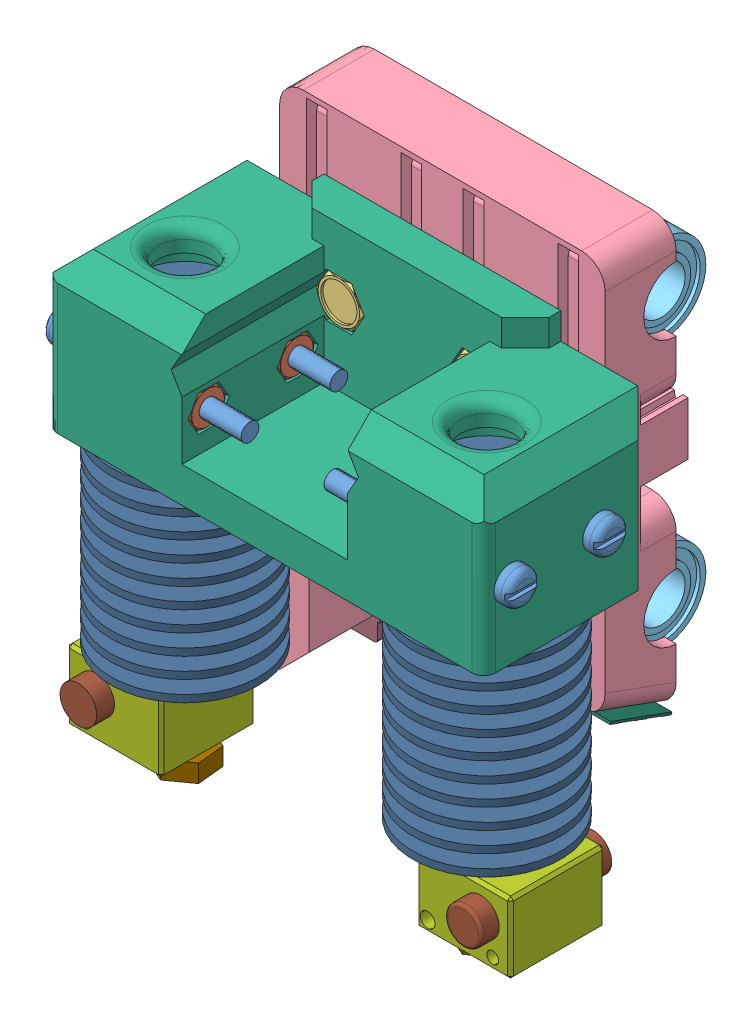
SolidWorks assembly extruder, configuration Défaut. Lengths in mm.
Overall size (79.79 92.4 60).
40 component instances, 15 part files, 73 mates.
Components (placement in the parent):
- pan slot head_am-1: pan slot head_am [B18.6.7M - M3 x 0.5 x 30 Slotted PHMS --30N] at (-39.4 4.5 25.5) size (32.4 5.6 5.6)
- pan slot head_am-2: pan slot head_am [B18.6.7M - M3 x 0.5 x 30 Slotted PHMS --30N] at (-39.4 4.5 10.5) size (32.4 5.6 5.6)
- pan slot head_am-3: pan slot head_am [B18.6.7M - M3 x 0.5 x 30 Slotted PHMS --30N] at (39.4 4.5 25.5) x (-1 0 0) z (0 0 1) size (32.4 5.6 5.6)
- pan slot head_am-4: pan slot head_am [B18.6.7M - M3 x 0.5 x 30 Slotted PHMS --30N] at (39.4 4.5 10.5) x (-1 0 0) z (0 0 1) size (32.4 5.6 5.6)
- hex nut style 1_am-1: hex nut style 1_am [B18.2.4.1M - Hex nut, Style 1,  M3 x 0.5 --D-N] at (-16.5 4.5 25.5) x (0 -1 0) z (-1 0 0) size (5.5 6.35 2.4)
- hex nut style 1_am-2: hex nut style 1_am [B18.2.4.1M - Hex nut, Style 1,  M3 x 0.5 --D-N] at (-16.5 4.5 10.5) x (0 -1 0) z (-1 0 0) size (5.5 6.35 2.4)
- hex nut style 1_am-3: hex nut style 1_am [B18.2.4.1M - Hex nut, Style 1,  M3 x 0.5 --D-N] at (16.5 4.5 25.5) x (0 -0.5 -0.866025) z (1 0 0) size (5.5 6.35 2.4)
- hex nut style 1_am-4: hex nut style 1_am [B18.2.4.1M - Hex nut, Style 1,  M3 x 0.5 --D-N] at (16.5 4.5 10.5) x (0 1 0) z (1 0 0) size (5.5 6.35 2.4)
- hex screw_am-3: hex screw_am [B18.6.7M - M4 x 0.7 x 20 Indented HHMS --20N] at (11.5 11.5 6) x (0 0 -1) z (0.866025 0.5 0) size (23 8.08 7)
- hex screw_am-4: hex screw_am [B18.6.7M - M4 x 0.7 x 20 Indented HHMS --20N] at (-11.5 11.5 6) x (0 0 -1) z (0.866025 -0.5 0) size (23 8.08 7)
- hex screw_am-5: hex screw_am [B18.6.7M - M4 x 0.7 x 20 Indented HHMS --20N] at (-11.5 -11.5 6) x (0 0 -1) z (0.866025 -0.5 0) size (23 8.08 7)
- hex screw_am-6: hex screw_am [B18.6.7M - M4 x 0.7 x 20 Indented HHMS --20N] at (11.5 -11.5 6) x (0 0 -1) z (0.866025 0.5 0) size (23 8.08 7)
- hex nut style 1_am-5: hex nut style 1_am [B18.2.4.1M - Hex nut, Style 1,  M4 x 0.7 --D-N] at (-11.5 11.5 -12) x (0.866025 -0.5 0) z (0 0 1) size (7 8.08 3.2)
- hex nut style 1_am-6: hex nut style 1_am [B18.2.4.1M - Hex nut, Style 1,  M4 x 0.7 --D-N] at (11.5 11.5 -12) x (0.866025 -0.5 0) z (0 0 1) size (7 8.08 3.2)
- hex nut style 1_am-7: hex nut style 1_am [B18.2.4.1M - Hex nut, Style 1,  M4 x 0.7 --D-N] at (11.5 -11.5 -12) x (0.866025 -0.5 0) z (0 0 1) size (7 8.08 3.2)
- hex nut style 1_am-8: hex nut style 1_am [B18.2.4.1M - Hex nut, Style 1,  M4 x 0.7 --D-N] at (-11.5 -11.5 -12) x (0.866025 -0.5 0) z (0 0 1) size (7 8.08 3.2)
- x_carriage-1: x_carriage [Défaut] at origin size (60 86.75 14)
- bearing_lm8uu-1: bearing_lm8uu [Défaut] at (25 22.5 -12) x (0 1 0) z (0 0 1) size (15 24 15)
- bearing_lm8uu-2: bearing_lm8uu [Défaut] at (-25 22.5 -12) x (0 1 0) z (0 0 -1) size (15 24 15)
- bearing_lm8uu-3: bearing_lm8uu [Défaut] at (25 -22.5 -12) x (0 -1 0) z (0 0 -1) size (15 24 15)
- bearing_lm8uu-4: bearing_lm8uu [Défaut] at (-25 -22.5 -12) x (0 -1 0) z (0 0 1) size (15 24 15)
- extruder_holder-1: extruder_holder [Défaut] at (-20 3 6) x (-1 0 0) z (0 0 -1) size (74 40 30)
- E3D-1: E3D [Default] at (-29.5 -53.4 18) x (-1 0 0) z (0 0 -1) size (28.79 69.7 37.75)
  - E3D Heat Block-1: E3D Heat Block [Default] at origin size (16 12 16)
  - E3D Heatbreak-1: E3D Heatbreak [Default] at (-4 19.55 0) x (-0.93266 0 -0.360757) z (-0.360757 0 0.93266) size (6 25.1 6)
  - E3D Nozzle-1: E3D Nozzle [Default] at (-4 -3.5 0) x (-0.097107 0 -0.995274) z (0.995274 0 -0.097107) size (9.24 12.5 8)
  - E3D Heatsink-1: E3D Heatsink [1.75 Bowden] at (-4 39.15 0) x (0.986263 0 -0.165183) z (0.165183 0 0.986263) size (25 50.1 25)
  - cartridge heater-1: cartridge heater [Default] at (3 7 0) x (0 0 1) z (-0.150948 -0.988542 0) size (32 6.2 6.2)
  - thermistor-1: thermistor [Default] at (-6 2 6.5) x (-0.997586 0.069447 0) z (-0.069447 -0.997586 0) size (2 13.25 2)
- E3D-2: E3D [Default] at (29.5 -53.4 18) size (28.79 69.7 37.75)
  - E3D Heat Block-1: E3D Heat Block [Default] at origin size (16 12 16)
  - E3D Heatbreak-1: E3D Heatbreak [Default] at (-4 19.55 0) x (-0.93266 0 -0.360757) z (-0.360757 0 0.93266) size (6 25.1 6)
  - E3D Nozzle-1: E3D Nozzle [Default] at (-4 -3.5 0) x (-0.097107 0 -0.995274) z (0.995274 0 -0.097107) size (9.24 12.5 8)
  - E3D Heatsink-1: E3D Heatsink [1.75 Bowden] at (-4 39.15 0) x (0.986263 0 -0.165183) z (0.165183 0 0.986263) size (25 50.1 25)
  - cartridge heater-1: cartridge heater [Default] at (3 7 0) x (0 0 1) z (-0.150948 -0.988542 0) size (32 6.2 6.2)
  - thermistor-1: thermistor [Default] at (-6 2 6.5) x (-0.997586 0.069447 0) z (-0.069447 -0.997586 0) size (2 13.25 2)
- kw4A(S) microswitch-1: kw4A(S) microswitch [Default] at (-22.975 -43.25 -18.5) x (0 0 1) z (0 -1 0) size (6.5 20.24 21.62)
- socket head cap screw_am-1: socket head cap screw_am [B18.3.1M - 2.5 x 0.45 x 10 Hex SHCS -- 10NHX] at (-25.5 -38.4 -21) x (0 0 1) z (-0.866025 -0.5 0) size (12.5 4.5 4.5)
- socket head cap screw_am-2: socket head cap screw_am [B18.3.1M - 2.5 x 0.45 x 10 Hex SHCS -- 10NHX] at (-25.5 -48.1 -21) x (0 0 1) z (-0.866025 -0.5 0) size (12.5 4.5 4.5)
- flexstripe24v-1: flexstripe24v [Default] at (2.5 -35.7231 -6.108) x (1 0 0) z (0 -0.34202 -0.939693) size (50 1.9 11)
Mates (geometry in assembly coordinates):
- Coaxiale1: concentric aligned: cylinder of x_carriage-1 through (1 22.5 -12) axis (1 0 0) radius 7.5; cylinder of bearing_lm8uu-1 through (13 22.5 -12) axis (1 0 0) radius 7.5
- Coïncidente1: coincident anti-aligned: plane of x_carriage-1 through (1 22.5 -12) normal (1 0 0); plane of bearing_lm8uu-1 through (1 22.5 -12) normal (-1 0 0)
- Parallèle1: parallel aligned: plane of bearing_lm8uu-1 through (25 22.5 -12) normal (0 0 1); plane of assembly through (0 0 0) normal (0 0 1)
- Coïncidente3: coincident anti-aligned: plane of x_carriage-1 through (0 0 0) normal (0 0 1); plane of extruder_holder-1 through (-20 3 0) normal (0 0 -1)
- Parallèle2: parallel anti-aligned: plane of extruder_holder-1 through (-20 3 6) normal (-1 0 0); plane of assembly through (0 0 0) normal (1 0 0)
- Coaxiale2: concentric anti-aligned: cylinder of x_carriage-1 through (-11.5 11.5 -14) axis (0 0 1) radius 2.5; cylinder of extruder_holder-1 through (-11.5 11.5 30) axis (0 0 -1) radius 2.5
- Coaxiale3: concentric aligned: cylinder of E3D-1/E3D Heatsink-1 through (-25.5 -39.3 18) axis (0 -1 0) radius 6; cylinder of extruder_holder-1 through (-25.5 18.5 18) axis (0 -1 0) radius 4.5
- Parallèle3: parallel aligned: plane of E3D-1/E3D Heat Block-1 through (-37.5 -41.4 10) normal (-1 0 0); plane of extruder_holder-1 through (-37 -1.5 30) normal (-1 0 0)
- Coaxiale4: concentric aligned: cylinder of extruder_holder-1 through (25.5 18.5 18) axis (0 -1 0) radius 4.5; cylinder of E3D-2/E3D Heatsink-1 through (25.5 -39.3 18) axis (0 -1 0) radius 8
- Parallèle4: parallel aligned: plane of extruder_holder-1 through (37 -1.5 30) normal (1 0 0); plane of E3D-2/E3D Heat Block-1 through (37.5 -41.4 26) normal (1 0 0)
- Coaxiale5: concentric aligned: cylinder of extruder_holder-1 through (-9.0503 4.5 25.5) axis (-1 0 0) radius 1.75; cylinder of pan slot head_am-1 through (-64.8 4.5 25.5) axis (-1 0 0) radius 2.8
- Coïncidente7: coincident anti-aligned: plane of extruder_holder-1 through (-37 -1.5 30) normal (-1 0 0); plane of pan slot head_am-1 through (-37 6 25.5) normal (1 0 0)
- Coaxiale6: concentric aligned: cylinder of extruder_holder-1 through (-9.0503 4.5 10.5) axis (-1 0 0) radius 1.75; cylinder of pan slot head_am-2 through (-64.8 4.5 10.5) axis (-1 0 0) radius 2.8
- Coïncidente8: coincident anti-aligned: plane of extruder_holder-1 through (-37 -1.5 30) normal (-1 0 0); plane of pan slot head_am-2 through (-37 6 10.5) normal (1 0 0)
- Coaxiale7: concentric aligned: cylinder of extruder_holder-1 through (9.0503 4.5 25.5) axis (1 0 0) radius 1.75; cylinder of pan slot head_am-3 through (64.8 4.5 25.5) axis (1 0 0) radius 2.8
- Coïncidente9: coincident anti-aligned: plane of extruder_holder-1 through (37 -1.5 30) normal (1 0 0); plane of pan slot head_am-3 through (37 3 25.5) normal (-1 0 0)
- Coaxiale8: concentric aligned: cylinder of extruder_holder-1 through (9.0503 4.5 10.5) axis (1 0 0) radius 1.75; cylinder of pan slot head_am-4 through (64.8 4.5 10.5) axis (1 0 0) radius 2.8
- Coïncidente10: coincident anti-aligned: plane of extruder_holder-1 through (37 -1.5 30) normal (1 0 0); plane of pan slot head_am-4 through (37 3 10.5) normal (-1 0 0)
- Coaxiale9: concentric aligned: cylinder of pan slot head_am-1 through (-64.8 4.5 25.5) axis (-1 0 0) radius 1.5; cylinder of hex nut style 1_am-1 through (8.5375 4.5 25.5) axis (-1 0 0) radius 1.5
- Coaxiale10: concentric aligned: cylinder of pan slot head_am-2 through (-64.8 4.5 10.5) axis (-1 0 0) radius 1.5; cylinder of hex nut style 1_am-2 through (8.5375 4.5 10.5) axis (-1 0 0) radius 1.5
- Coaxiale11: concentric aligned: cylinder of pan slot head_am-3 through (64.8 4.5 25.5) axis (1 0 0) radius 1.5; cylinder of hex nut style 1_am-3 through (-8.5375 4.5 25.5) axis (1 0 0) radius 1.5
- Coaxiale12: concentric aligned: cylinder of pan slot head_am-4 through (64.8 4.5 10.5) axis (1 0 0) radius 1.5; cylinder of hex nut style 1_am-4 through (-8.5375 4.5 10.5) axis (1 0 0) radius 1.5
- Coïncidente11: coincident anti-aligned: plane of extruder_holder-1 through (-16.5 3 6) normal (1 0 0); plane of hex nut style 1_am-2 through (-16.5 4.5 13.6754) normal (-1 0 0)
- Coïncidente12: coincident anti-aligned: plane of extruder_holder-1 through (-16.5 3 6) normal (1 0 0); plane of hex nut style 1_am-1 through (-16.5 4.5 28.6754) normal (-1 0 0)
- Coïncidente13: coincident anti-aligned: plane of extruder_holder-1 through (16.5 3 6) normal (-1 0 0); plane of hex nut style 1_am-3 through (16.5 7.25 23.9123) normal (1 0 0)
- Coïncidente14: coincident anti-aligned: plane of extruder_holder-1 through (16.5 3 6) normal (-1 0 0); plane of hex nut style 1_am-4 through (16.5 4.5 13.6754) normal (1 0 0)
- Parallèle5: parallel aligned: plane of extruder_holder-1 through (-16.5 4.5 22.0359) normal (0 -0.5 0.866025); plane of hex nut style 1_am-1 through (-14.1 1.75 27.0877) normal (0 -0.5 0.866025)
- Parallèle6: parallel aligned: plane of extruder_holder-1 through (-16.5 4.5 7.0359) normal (0 -0.5 0.866025); plane of hex nut style 1_am-2 through (-14.1 1.75 12.0877) normal (0 -0.5 0.866025)
- Coaxiale13: concentric anti-aligned: cylinder of extruder_holder-1 through (11.5 11.5 30) axis (0 0 -1) radius 2.5; cylinder of hex screw_am-3 through (11.5 11.5 31.4) axis (0 0 1) radius 2
- Coïncidente15: coincident anti-aligned: plane of extruder_holder-1 through (-20 3 3) normal (0 0 1); plane of hex screw_am-3 through (10.5 13.2321 3) normal (0 0 -1)
- Coaxiale14: concentric anti-aligned: cylinder of extruder_holder-1 through (-11.5 11.5 30) axis (0 0 -1) radius 2.5; cylinder of hex screw_am-4 through (-11.5 11.5 31.4) axis (0 0 1) radius 2
- Coïncidente16: coincident anti-aligned: plane of extruder_holder-1 through (-20 3 3) normal (0 0 1); plane of hex screw_am-4 through (-10.5 13.2321 3) normal (0 0 -1)
- Coaxiale15: concentric anti-aligned: cylinder of extruder_holder-1 through (-11.5 -11.5 30) axis (0 0 -1) radius 2.5; cylinder of hex screw_am-5 through (-11.5 -11.5 31.4) axis (0 0 1) radius 2
- Coïncidente17: coincident anti-aligned: plane of extruder_holder-1 through (-20 3 3) normal (0 0 1); plane of hex screw_am-5 through (-10.5 -9.7679 3) normal (0 0 -1)
- Coaxiale16: concentric anti-aligned: cylinder of extruder_holder-1 through (11.5 -11.5 30) axis (0 0 -1) radius 2.5; cylinder of hex screw_am-6 through (11.5 -11.5 31.4) axis (0 0 1) radius 2
- Coïncidente18: coincident anti-aligned: plane of extruder_holder-1 through (-20 3 3) normal (0 0 1); plane of hex screw_am-6 through (10.5 -9.7679 3) normal (0 0 -1)
- Parallèle7: parallel aligned: plane of extruder_holder-1 through (-13.6651 15.25 30) normal (0.866025 -0.5 0); plane of hex screw_am-4 through (-9.4793 8 3) normal (0.866025 -0.5 0)
- Parallèle8: parallel aligned: plane of extruder_holder-1 through (-13.6651 -7.75 30) normal (0.866025 -0.5 0); plane of hex screw_am-5 through (-9.4793 -15 3) normal (0.866025 -0.5 0)
- Parallèle9: parallel aligned: plane of extruder_holder-1 through (15.8301 11.5 30) normal (-0.866025 -0.5 0); plane of hex screw_am-3 through (7.4585 11.5 3) normal (-0.866025 -0.5 0)
- Parallèle10: parallel aligned: plane of extruder_holder-1 through (15.8301 -11.5 30) normal (-0.866025 -0.5 0); plane of hex screw_am-6 through (7.4585 -11.5 3) normal (-0.866025 -0.5 0)
- Coaxiale17: concentric aligned: cylinder of hex screw_am-4 through (-11.5 11.5 31.4) axis (0 0 1) radius 2; cylinder of hex nut style 1_am-5 through (-11.5 11.5 -37.0375) axis (0 0 1) radius 2
- Coaxiale18: concentric aligned: cylinder of hex screw_am-3 through (11.5 11.5 31.4) axis (0 0 1) radius 2; cylinder of hex nut style 1_am-6 through (11.5 11.5 -37.0375) axis (0 0 1) radius 2
- Coaxiale19: concentric aligned: cylinder of hex screw_am-6 through (11.5 -11.5 31.4) axis (0 0 1) radius 2; cylinder of hex nut style 1_am-7 through (11.5 -11.5 -37.0375) axis (0 0 1) radius 2
- Coaxiale20: concentric aligned: cylinder of hex screw_am-5 through (-11.5 -11.5 31.4) axis (0 0 1) radius 2; cylinder of hex nut style 1_am-8 through (-11.5 -11.5 -37.0375) axis (0 0 1) radius 2
- Coïncidente20: coincident anti-aligned: plane of x_carriage-1 through (0 0 -12) normal (0 0 -1); plane of hex nut style 1_am-6 through (5.4378 15 -12) normal (0 0 1)
- Coïncidente21: coincident anti-aligned: plane of x_carriage-1 through (0 0 -12) normal (0 0 -1); plane of hex nut style 1_am-5 through (-17.5622 15 -12) normal (0 0 1)
- Coïncidente22: coincident anti-aligned: plane of x_carriage-1 through (0 0 -12) normal (0 0 -1); plane of hex nut style 1_am-7 through (5.4378 -8 -12) normal (0 0 1)
- Coïncidente23: coincident anti-aligned: plane of x_carriage-1 through (0 0 -12) normal (0 0 -1); plane of hex nut style 1_am-8 through (-17.5622 -8 -12) normal (0 0 1)
- Parallèle12: parallel aligned: plane of x_carriage-1 through (27.5 -7.5 -12) normal (0 1 0); plane of hex nut style 1_am-7 through (13.5207 -8 -15.2) normal (0 1 0)
- Parallèle13: parallel aligned: plane of x_carriage-1 through (27.5 -7.5 -12) normal (0 1 0); plane of hex nut style 1_am-8 through (-9.4793 -8 -15.2) normal (0 1 0)
- Parallèle14: parallel aligned: plane of x_carriage-1 through (27.5 7.5 -12) normal (0 -1 0); plane of hex nut style 1_am-6 through (9.4793 8 -15.2) normal (0 -1 0)
- Parallèle15: parallel aligned: plane of x_carriage-1 through (27.5 7.5 -12) normal (0 -1 0); plane of hex nut style 1_am-5 through (-13.5207 8 -15.2) normal (0 -1 0)
- Parallèle16: parallel aligned: line of pan slot head_am-1 through (-38.7 4 22.856) axis (0 0 1); line of pan slot head_am-2 through (-38.7 4 7.856) axis (0 0 1)
- Parallèle17: parallel anti-aligned: line of extruder_holder-1 through (-37 -7.5 28) axis (0 0 -1); line of pan slot head_am-2 through (-38.7 4 7.856) axis (0 0 1)
- Parallèle18: parallel anti-aligned: plane of extruder_holder-1 through (16.5 7.5 23.7679) normal (0 -1 0); plane of hex nut style 1_am-3 through (14.1 7.25 23.9123) normal (0 1 0)
- Parallèle19: parallel aligned: plane of extruder_holder-1 through (16.5 4.5 7.0359) normal (0 -0.5 0.866025); plane of hex nut style 1_am-4 through (14.1 4.5 13.6754) normal (0 -0.5 0.866025)
- Parallèle20: parallel aligned: line of pan slot head_am-3 through (38.7 5 22.856) axis (0 0 1); line of pan slot head_am-4 through (38.7 5 7.856) axis (0 0 1)
- Parallèle21: parallel anti-aligned: line of extruder_holder-1 through (37 -7.5 28) axis (0 0 -1); line of pan slot head_am-3 through (38.7 5 22.856) axis (0 0 1)
- Coïncidente25: coincident anti-aligned: plane of x_carriage-1 through (0 0 -12) normal (0 0 -1); plane of kw4A(S) microswitch-1 through (-31.995 -34 -12) normal (0 0 1)
- Parallèle23: parallel aligned: plane of x_carriage-1 through (-27.5 33.5 -6) normal (0 1 0); plane of kw4A(S) microswitch-1 through (-31.995 -33.5 -12) normal (0 1 0)
- Coaxiale21: concentric aligned: cylinder of kw4A(S) microswitch-1 through (-25.5 -38.4 -12) axis (0 0 -1) radius 1.275; cylinder of socket head cap screw_am-1 through (-25.5 -38.4 -52.75) axis (0 0 -1) radius 2.25
- Coïncidente28: coincident anti-aligned: plane of kw4A(S) microswitch-1 through (-31.995 -34 -18.5) normal (0 0 -1); plane of socket head cap screw_am-1 through (-26.625 -36.4514 -18.5) normal (0 0 1)
- Coaxiale22: concentric aligned: cylinder of kw4A(S) microswitch-1 through (-25.5 -48.1 -12) axis (0 0 -1) radius 1.275; cylinder of socket head cap screw_am-2 through (-25.5 -48.1 -52.75) axis (0 0 -1) radius 2.25
- Coïncidente29: coincident anti-aligned: plane of kw4A(S) microswitch-1 through (-31.995 -34 -18.5) normal (0 0 -1); plane of socket head cap screw_am-2 through (-26.625 -46.1514 -18.5) normal (0 0 1)
- Parallèle24: parallel aligned: plane of socket head cap screw_am-1 through (-26.0903 -39.4225 -19.9) normal (0 1 0); plane of socket head cap screw_am-2 through (-26.0903 -49.1225 -19.9) normal (0 1 0)
- Parallèle25: parallel aligned: plane of kw4A(S) microswitch-1 through (-31.995 -33.5 -12) normal (0 1 0); plane of socket head cap screw_am-1 through (-26.0903 -39.4225 -19.9) normal (0 1 0)
- Coaxiale23: concentric anti-aligned: cylinder of x_carriage-1 through (-25.5 -38.4 -8) axis (0 0 -1) radius 1; circle of kw4A(S) microswitch-1
- Coïncidente31: coincident anti-aligned: plane of x_carriage-1 through (27.5 -37.8676 -12) normal (0 -0.939693 0.34202); plane of flexstripe24v-1 through (2.5 -35.7231 -6.108) normal (0 0.939693 -0.34202)
- Parallèle26: parallel anti-aligned: line of x_carriage-1 through (-22.5 -33.5 0) axis (1 0 0); line of flexstripe24v-1 through (27.5 -33.842 -0.9397) axis (-1 0 0)
- Coïncidente32: coincident anti-aligned: plane of x_carriage-1 through (-22.5 -53.25 0) normal (1 0 0); plane of flexstripe24v-1 through (-22.5 -37.9801 -11.1395) normal (-1 0 0)
- Distance1: distance = 1 mm: line of flexstripe24v-1 through (27.5 -33.842 -0.9397) axis (-1 0 0); line of x_carriage-1 through (-22.5 -33.5 0) axis (1 0 0)
- Coïncidente33: coincident anti-aligned: plane of extruder_holder-1 through (-20 -7.5 6) normal (0 -1 0); plane of E3D-1/E3D Heatsink-1 through (-37.8283 -7.5 20.0648) normal (0 1 0)
- Coïncidente34: coincident anti-aligned: plane of extruder_holder-1 through (-20 -7.5 6) normal (0 -1 0); plane of E3D-2/E3D Heatsink-1 through (37.8283 -7.5 15.9352) normal (0 1 0)
